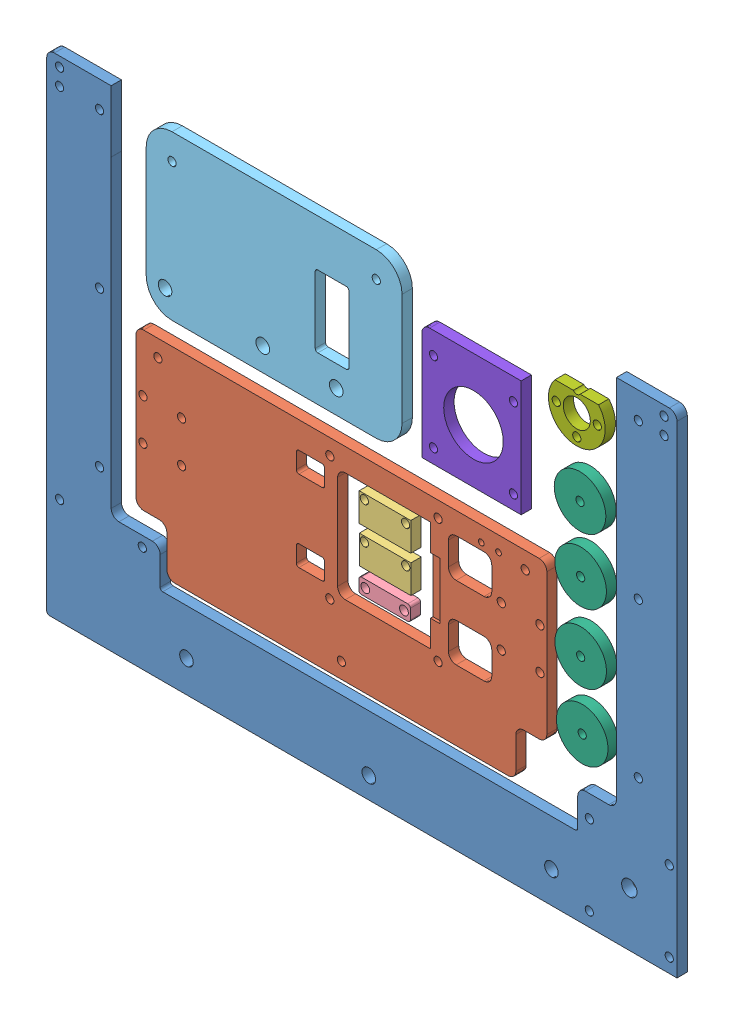
SolidWorks assembly Z AND Y FRAME PLUS SMALL ONES4, configuration Default. Lengths in mm.
Overall size (255.5 200 4).
12 component instances, 8 part files, 19 mates.
Components (placement in the parent):
- Z Frame-2: Z Frame [Valor predeterminado] at (-101.1725 37.5207 0) size (250 190 4)
- Bed Support2-3: Bed Support2 [Default] at (31.4027 -73.1228 4) x (-1 0 0) z (0 0 -1) size (159.38 135.83 4)
- BELT HOLDER-3: BELT HOLDER [Default] at (-20.0811 -6.5358 4) x (-1 0 0) z (0 0 -1) size (20.01 11 4)
- BELT HOLDER-4: BELT HOLDER [Default] at (-20.0363 -20.7491 4) x (-1 0 0) z (0 0 -1) size (20.01 11 4)
- Hotend bracket-3: Hotend bracket [Valor predeterminado] at (-72.0957 -68.0472 137.3657) x (-1 0 0) z (0 0 -1) size (19.93 5.9 4)
- Small foot2-3: Small foot2 [Default] at (223.7937 -22.704 0) x (0 -1 0) z (0 0 1) size (63.38 99.24 4)
- foot-1: foot [Default] at (-72.662 -313.517 0) x (-1 0 0) z (0 0 1) size (20 20 4)
- foot-2: foot [Default] at (123.6711 265.2856 0) size (20 20 4)
- foot-3: foot [Default] at (123.6648 292.063 0) size (20 20 4)
- foot-4: foot [Default] at (123.4165 317.2045 0) size (20 20 4)
- Z nut atachment to X Bridge-1: Z nut atachment to X Bridge [Valor predeterminado] at (-79.9476 372.4659 0) size (22 18.05 4)
- motor spacer-1: motor spacer [Default] at (-60.4449 125.3732 0) size (38.5 45 4)
Mates (geometry in assembly coordinates):
- Coincident6: coincident anti-aligned: plane of Z Frame-2 through (-178.9289 86.4051 0) normal (0 0 -1); plane of assembly through (0 0 0) normal (0 0 1)
- Coincident7: coincident: plane of Z Frame-2 through (62.5711 -100.5949 4) normal (1 0 0); line of assembly
- Coincident8: coincident: plane of Z Frame-2 through (67.0711 -100.5949 4) normal (0 -1 0); line of assembly
- Coincident9: coincident aligned: plane of Z Frame-2 through (-178.9289 86.4051 4) normal (0 0 1); plane of Bed Support2-3 through (31.4027 -73.1228 4) normal (0 0 1)
- Coincident10: coincident aligned: plane of Bed Support2-3 through (31.4027 -73.1228 0) normal (0 0 -1); plane of BELT HOLDER-3 through (-20.0811 -6.5358 0) normal (0 0 -1)
- Coincident11: coincident aligned: plane of Z Frame-2 through (-178.9289 86.4051 4) normal (0 0 1); plane of Small foot2-3 through (223.7937 -22.704 4) normal (0 0 1)
- Parallel2: parallel anti-aligned: plane of Z Frame-2 through (-136.9289 -70.5949 4) normal (0 1 0); plane of Small foot2-3 through (-44.0757 22.3754 4) normal (0 -1 0)
- Coincident16: coincident aligned: plane of Z Frame-2 through (-178.9289 86.4051 4) normal (0 0 1); plane of foot-1 through (25.8016 -37.0118 4) normal (0 0 1)
- Coincident17: coincident aligned: plane of Z Frame-2 through (-178.9289 86.4051 4) normal (0 0 1); plane of motor spacer-1 through (-33.3739 66.7783 4) normal (0 0 1)
- Coincident19: coincident aligned: plane of Bed Support2-3 through (31.4027 -73.1228 0) normal (0 0 -1); plane of Hotend bracket-3 through (-72.0957 -68.0472 0) normal (0 0 -1)
- Coincident20: coincident aligned: plane of Bed Support2-3 through (31.4027 -73.1228 0) normal (0 0 -1); plane of BELT HOLDER-4 through (-20.0363 -20.7491 0) normal (0 0 -1)
- Coincident21: coincident aligned: plane of Z Frame-2 through (-178.9289 86.4051 0) normal (0 0 -1); plane of foot-2 through (25.2075 -11.2195 0) normal (0 0 -1)
- Coincident22: coincident aligned: plane of Z Frame-2 through (-178.9289 86.4051 0) normal (0 0 -1); plane of foot-3 through (25.2012 15.5578 0) normal (0 0 -1)
- Coincident23: coincident aligned: plane of Z Frame-2 through (-178.9289 86.4051 0) normal (0 0 -1); plane of foot-4 through (24.9529 40.6994 0) normal (0 0 -1)
- Coincident25: coincident aligned: plane of Z Frame-2 through (-178.9289 86.4051 0) normal (0 0 -1); plane of Z nut atachment to X Bridge-1 through (23.699 69.7 0) normal (0 0 -1)
- Parallel3: parallel: line of Z Frame-2 through (-136.9289 -70.5949 4) axis (1 0 0); plane of Bed Support2-3 through (0.0919 -65.3857 0) normal (0 -1 0)
- Parallel4: parallel: line of Bed Support2-3 through (-66.0986 -37.8425 4) axis (1 0 0); plane of Hotend bracket-3 through (-40.8736 -33.0074 0) normal (0 -1 0)
- Parallel5: parallel anti-aligned: line of Bed Support2-3 through (-66.0986 -37.8425 4) axis (1 0 0); line of BELT HOLDER-4 through (-40.6549 -23.7491 4) axis (-1 0 0)
- Parallel6: parallel anti-aligned: line of Bed Support2-3 through (-66.0986 -37.8425 4) axis (1 0 0); line of BELT HOLDER-3 through (-40.6996 -9.5358 4) axis (-1 0 0)
